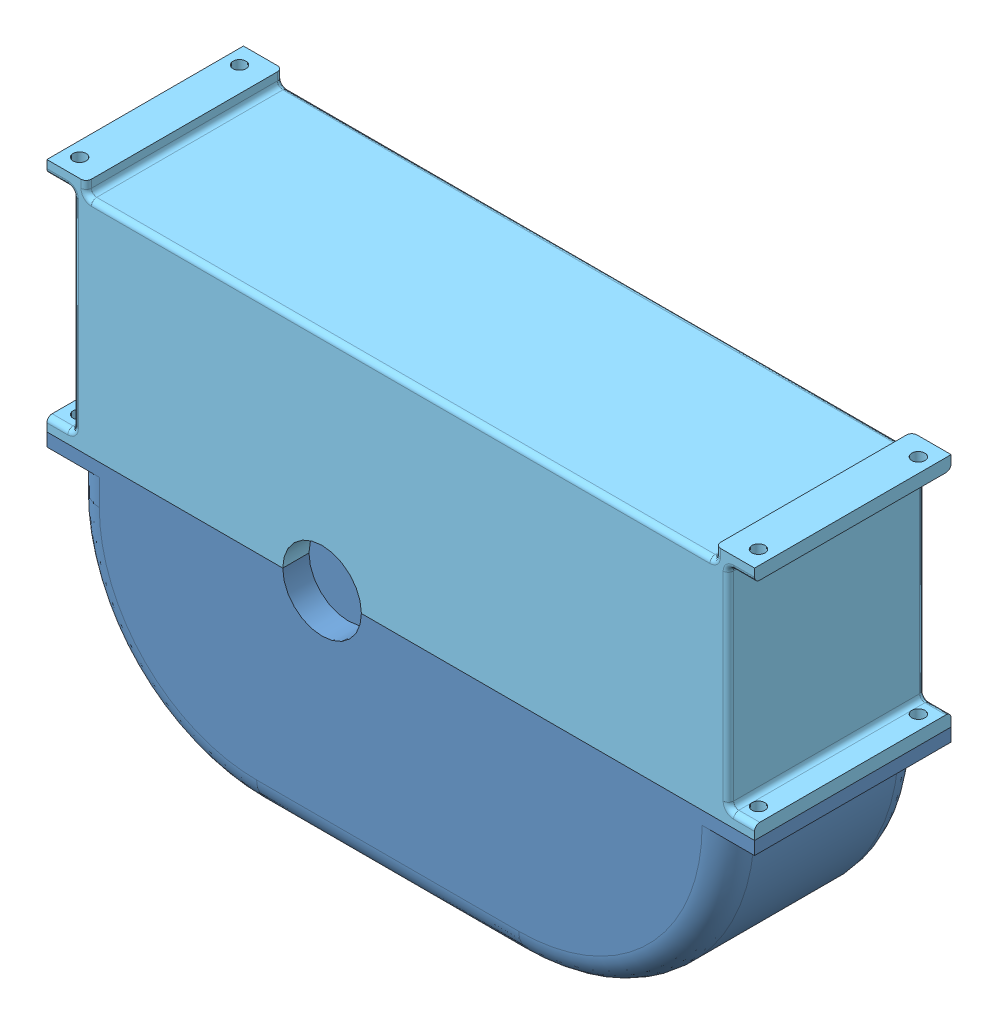
SolidWorks assembly check_Gear, configuration Default. Lengths in mm.
Overall size (270 175 86).
5 component instances, 5 part files, 9 mates.
Components (placement in the parent):
- Gearbox-1: Gearbox [Default] at origin size (270 85 75)
- gear2_shaft-1: gear2_shaft [Default] at (54 0 -31.5) x (0.362022 0.932169 0) z (0 0 1) size (10 10 63)
- Gear45_shaft-1: Gear45_shaft [Default] at (-18 0 -32) x (0.953511 0.30136 0) z (0 0 1) size (10 10 29)
- motor_shaft-1: motor_shaft [Default] at (-54 0 -48.5) x (-0.993126 0.117049 0) z (0 0 1) size (7.5 7.5 45)
- upper gear-2: upper gear [Default] at origin size (270 90 75)
Mates (geometry in assembly coordinates):
- Concentric1: concentric anti-aligned: circle of Gearbox-1; circle of Gear45_shaft-1
- Concentric2: concentric aligned: circle of Gearbox-1; circle of gear2_shaft-1
- Concentric3: concentric anti-aligned: circle of Gearbox-1; circle of motor_shaft-1
- Distance2: distance = 1 mm anti-aligned: plane of Gearbox-1 through (0 0 -32.5) normal (0 0 1); plane of gear2_shaft-1 through (54 0 -31.5) normal (0 0 -1)
- Distance3: distance = 0.5 mm anti-aligned: plane of Gear45_shaft-1 through (-18 0 -3) normal (0 0 1); plane of Gearbox-1 through (-115 -305.4886 -2.5) normal (0 0 -1)
- Distance4: distance = 1 mm anti-aligned: plane of motor_shaft-1 through (-54 0 -3.5) normal (0 0 1); plane of Gearbox-1 through (-115 -305.4886 -2.5) normal (0 0 -1)
- Concentric13: concentric anti-aligned: cylinder of Gearbox-1; cylinder of upper gear-2 through (-129.5 5 -30.5) axis (0 -1 0) radius 2.5
- Concentric14: concentric anti-aligned: circle of Gearbox-1; circle of upper gear-2
- Coincident19: coincident anti-aligned: plane of Gearbox-1 through (125 0 37.5) normal (0 1 0); plane of upper gear-2 through (0 0 0) normal (0 -1 0)
